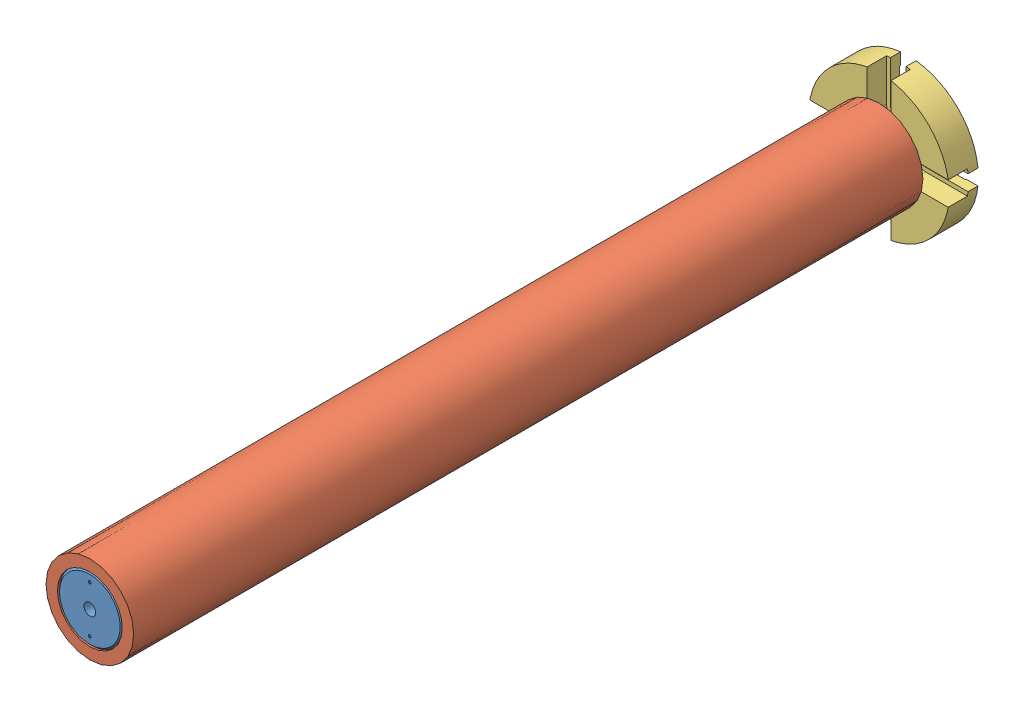
SolidWorks assembly Damped Post for Main Chamber Bottom, configuration Default. Lengths in mm.
Overall size (60.59 60.59 356.82).
4 component instances, 3 part files, 6 mates.
Components (placement in the parent):
- Damped Post for Main Chamber P2_90322A235-1: Damped Post for Main Chamber P2_90322A235 [90322A235] at (-6.5102 22.1457 41.8672) size (32.66 32.53 40.54)
- Damped Post for Main Chamber P2_90322A235-2: Damped Post for Main Chamber P2_90322A235 [90322A235] at (-6.5102 22.1457 -262.9328) x (-0.923728 -0.383049 0) z (0 0 -1) size (32.66 32.53 40.54)
- Damped Post for Main Chamber Bottom P1-1: Damped Post for Main Chamber Bottom P1 [Default] at (-6.5102 22.1457 -281.9828) x (1 0 0) z (0 -1 0) size (38.1 342.9 38.1)
- Damped Post for Main Chamber P3_PB2-1: Damped Post for Main Chamber P3_PB2 [Default] at (-6.5102 22.1457 -288.3328) x (1 0 0) z (0 -1 0) size (60.59 12.7 60.59)
Mates (geometry in assembly coordinates):
- Concentric1: concentric aligned: circle of Damped Post for Main Chamber P2_90322A235-1; circle of Damped Post for Main Chamber Bottom P1-1
- Coincident1: coincident aligned: plane of Damped Post for Main Chamber P2_90322A235-1 through (-6.5102 22.1457 60.9172) normal (0 0 1); plane of Damped Post for Main Chamber Bottom P1-1 through (-6.5102 22.1457 60.9172) normal (0 0 1)
- Concentric2: concentric anti-aligned: circle of Damped Post for Main Chamber P2_90322A235-2; circle of Damped Post for Main Chamber Bottom P1-1
- Coincident2: coincident aligned: plane of Damped Post for Main Chamber P2_90322A235-2 through (-6.5102 22.1457 -281.9828) normal (0 0 -1); plane of Damped Post for Main Chamber Bottom P1-1 through (-6.5102 22.1457 -281.9828) normal (0 0 -1)
- Concentric3: concentric aligned: circle of Damped Post for Main Chamber P2_90322A235-2; circle of Damped Post for Main Chamber P3_PB2-1
- Coincident3: coincident anti-aligned: plane of Damped Post for Main Chamber Bottom P1-1 through (-6.5102 22.1457 -281.9828) normal (0 0 -1); plane of Damped Post for Main Chamber P3_PB2-1 through (-6.5102 22.1457 -281.9828) normal (0 0 1)
